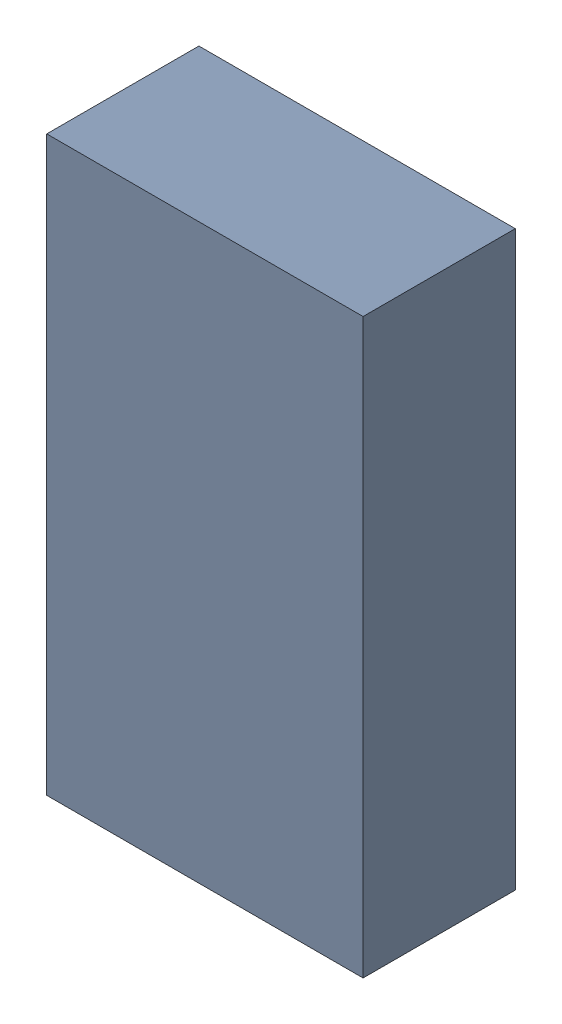
SolidWorks assembly U1, configuration Standard. Lengths in mm.
Overall size (3.7 6.7 1.78).
2 component instances, 1 part files, 0 mates.
Components (placement in the parent):
- 885544552-1: 885544552 [Standard] at (-11.565 19.3 0.02) size (3.7 6.7 1.78)
  - Extruded_33-1: Extruded_33 [Standard] at origin size (3.7 6.7 1.78)
